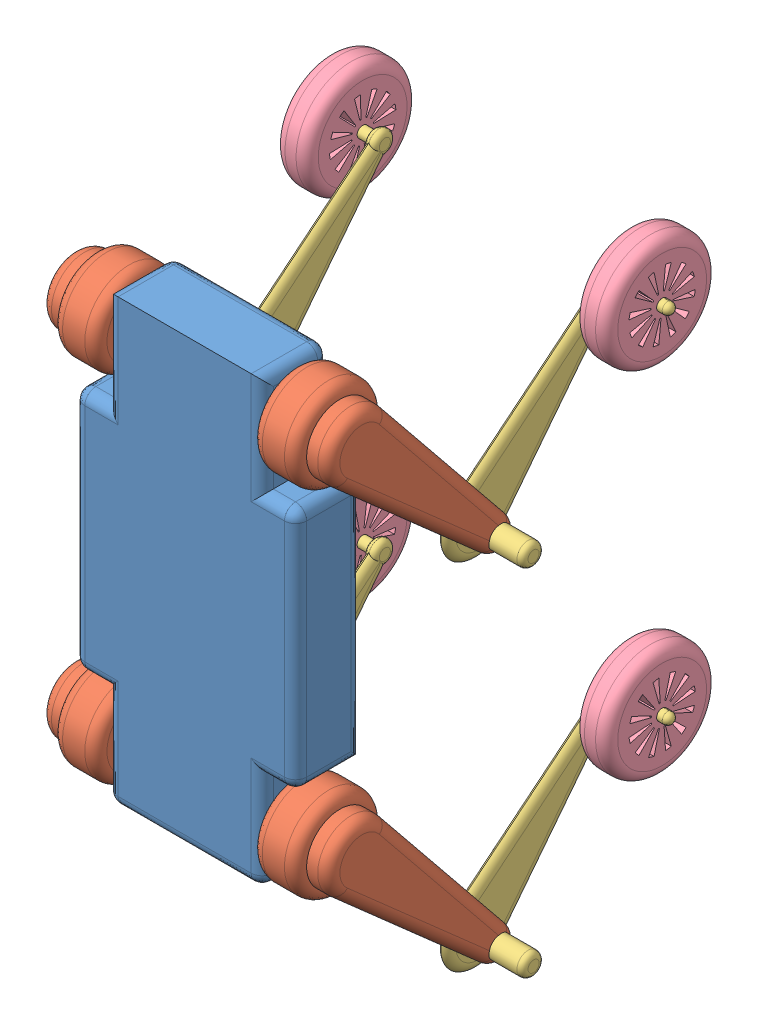
SolidWorks assembly Robot Assembly, configuration Default. Lengths in mm.
Overall size (320 555.26 377.09).
14 component instances, 5 part files, 32 mates.
Components (placement in the parent):
- Chassis-1: Chassis [Default] at (25.2853 23.51 279.6781) size (200 400 60)
- Leg Link-1: Leg Link [Default] at (235.2853 63.51 309.6781) x (1 0 0) z (0 0.721797 0.692105) size (100.59 80 235)
- Leg Link-2: Leg Link [Default] at (15.2853 383.51 309.6781) x (-1 0 0) z (0 0.721797 0.692105) size (100.59 80 235)
- Leg Link-3: Leg Link [Default] at (235.2853 383.51 309.6781) x (1 0 0) z (0 0.721797 0.692105) size (100.59 80 235)
- Leg Link-4: Leg Link [Default] at (15.2853 63.51 309.6781) x (-1 0 0) z (0 0.721797 0.692105) size (100.59 80 235)
- Part1^Robot Assembly-1: Part1^Robot Assembly [Default] at origin (virtual)
- Leg-1: Leg [Default] at (225.2853 -66.4135 185.0992) x (1 0 0) z (0 -0.714481 0.699655) size (60.46 57.32 218.66)
- Leg-2: Leg [Default] at (25.2853 253.5865 185.0992) x (-1 0 0) z (0 -0.714481 0.699655) size (60.46 57.32 218.66)
- Leg-3: Leg [Default] at (25.2853 -66.4135 185.0992) x (-1 0 0) z (0 -0.714481 0.699655) size (60.46 57.32 218.66)
- Leg-4: Leg [Default] at (225.2853 253.5865 185.0992) x (1 0 0) z (0 -0.714481 0.699655) size (60.46 57.32 218.66)
- Wheel-1: Wheel [Default] at (-24.7147 382.1931 59.1613) x (1 0 0) z (0 -0.969703 -0.244286) size (30 100 100)
- Wheel-2: Wheel [Default] at (245.2853 382.1931 59.1613) x (1 0 0) z (0 -0.911816 -0.410599) size (30 100 100)
- Wheel-3: Wheel [Default] at (-24.7147 62.1931 59.1613) x (1 0 0) z (0 -0.799104 0.601193) size (30 100 100)
- Wheel-4: Wheel [Default] at (245.2853 62.1931 59.1613) x (1 0 0) z (0 -0.274003 0.961729) size (30 100 100)
Mates (geometry in assembly coordinates):
- Concentric1: concentric: cylinder of Chassis-1 through (25.2853 63.51 309.6781) axis (1 0 0) radius 15; cylinder of Leg Link-1 through (155.2853 63.51 309.6781) axis (1 0 0) radius 15
- Coincident1: coincident: plane of Chassis-1 through (195.2853 113.51 339.6781) normal (1 0 0); plane of Leg Link-1 through (195.2853 63.51 309.6781) normal (-1 0 0)
- Concentric2: concentric: cylinder of Chassis-1 through (25.2853 63.51 309.6781) axis (1 0 0) radius 15; cylinder of Leg Link-4 through (95.2853 63.51 309.6781) axis (-1 0 0) radius 15
- Coincident2: coincident: plane of Chassis-1 through (55.2853 113.51 339.6781) normal (-1 0 0); plane of Leg Link-4 through (55.2853 63.51 309.6781) normal (1 0 0)
- Concentric3: concentric: cylinder of Chassis-1 through (25.2853 383.51 309.6781) axis (1 0 0) radius 15; cylinder of Leg Link-2 through (95.2853 383.51 309.6781) axis (-1 0 0) radius 15
- Coincident4: coincident: plane of Chassis-1 through (55.2853 333.51 339.6781) normal (-1 0 0); plane of Leg Link-2 through (55.2853 383.51 309.6781) normal (1 0 0)
- Concentric4: concentric: cylinder of Chassis-1 through (25.2853 383.51 309.6781) axis (1 0 0) radius 15; cylinder of Leg Link-3 through (155.2853 383.51 309.6781) axis (1 0 0) radius 15
- Coincident5: coincident: plane of Chassis-1 through (195.2853 333.51 339.6781) normal (1 0 0); plane of Leg Link-3 through (195.2853 383.51 309.6781) normal (-1 0 0)
- Concentric5: concentric: cylinder of Leg Link-1 through (155.2853 -66.4135 185.0992) axis (1 0 0) radius 10; cylinder of Leg-1 through (285.2853 -66.4135 185.0992) axis (-1 0 0) radius 10
- Coincident6: coincident: plane of Leg Link-1 through (235.2853 63.51 309.6781) normal (-1 0 0); plane of Leg-1 through (235.2853 -66.4135 185.0992) normal (1 0 0)
- Concentric6: concentric: cylinder of Leg Link-3 through (155.2853 253.5865 185.0992) axis (1 0 0) radius 10; cylinder of Leg-4 through (285.2853 253.5865 185.0992) axis (-1 0 0) radius 10
- Coincident7: coincident: plane of Leg Link-3 through (235.2853 383.51 309.6781) normal (-1 0 0); plane of Leg-4 through (235.2853 253.5865 185.0992) normal (1 0 0)
- Concentric7: concentric: cylinder of Leg Link-4 through (95.2853 -40.2556 162.5975) axis (-1 0 0) radius 10; cylinder of Leg-3 through (-34.7147 -40.2556 162.5975) axis (1 0 0) radius 10
- Coincident8: coincident: plane of Leg Link-4 through (15.2853 63.51 309.6781) normal (1 0 0); plane of Leg-3 through (15.2853 -40.2556 162.5975) normal (-1 0 0)
- Coincident9: coincident: plane of Leg Link-2 through (15.2853 383.51 309.6781) normal (1 0 0); plane of Leg-2 through (15.2853 253.5865 185.0992) normal (-1 0 0)
- Concentric8: concentric: cylinder of Leg Link-2 through (95.2853 253.5865 185.0992) axis (-1 0 0) radius 10; cylinder of Leg-2 through (-34.7147 253.5865 185.0992) axis (1 0 0) radius 10
- Concentric9: concentric: cylinder of Leg-2 through (-34.7147 382.1931 59.1613) axis (1 0 0) radius 5; cylinder of Wheel-1 through (-24.7147 382.1931 59.1613) axis (1 0 0) radius 5
- Concentric10: concentric: cylinder of Leg-4 through (285.2853 382.1931 59.1613) axis (-1 0 0) radius 5; cylinder of Wheel-2 through (245.2853 382.1931 59.1613) axis (1 0 0) radius 5
- Concentric11: concentric: cylinder of Leg-3 through (-34.7147 110.0182 63.5128) axis (1 0 0) radius 5; cylinder of Wheel-3 through (-24.7147 110.0182 63.5128) axis (1 0 0) radius 5
- Concentric12: concentric: cylinder of Leg-1 through (285.2853 62.1931 59.1613) axis (-1 0 0) radius 5; cylinder of Wheel-4 through (245.2853 62.1931 59.1613) axis (1 0 0) radius 5
- Distance2: distance = 10 mm: plane of Wheel-4 through (245.2853 62.1931 59.1613) normal (-1 0 0); plane of Leg-1 through (235.2853 -66.4135 185.0992) normal (1 0 0)
- Distance3: distance = 10 mm: plane of Wheel-2 through (245.2853 382.1931 59.1613) normal (-1 0 0); plane of Leg-4 through (235.2853 253.5865 185.0992) normal (1 0 0)
- Distance4: distance = 10 mm: plane of Wheel-3 through (5.2853 62.1931 59.1613) normal (1 0 0); plane of Leg-3 through (15.2853 -66.4135 185.0992) normal (-1 0 0)
- Distance5: distance = 10 mm: plane of Wheel-1 through (5.2853 382.1931 59.1613) normal (1 0 0); plane of Leg-2 through (15.2853 253.5865 185.0992) normal (-1 0 0)
- Angle2: planar angle = 2.460914 rad: line of Leg Link-1 through (255.2853 -56.5462 186.7234) axis (0 0.777146 0.62932); line of Chassis-1 through (215.2853 333.51 279.6781) axis (0 -1 0)
- Angle3: planar angle = 0.680678 rad: line of Leg Link-4 through (-4.7147 76.0964 294.1352) axis (0 -0.777146 -0.62932); line of Chassis-1 through (25.2853 323.51 289.6781) axis (0 -1 0)
- Angle4: planar angle = 0.680678 rad: line of Leg Link-3 through (255.2853 263.4538 186.7234) axis (0 0.777146 0.62932); line of Chassis-1 through (225.2853 123.51 289.6781) axis (0 1 0)
- Angle5: planar angle = 0.680678 rad: line of Leg Link-2 through (-4.7147 396.0964 294.1352) axis (0 -0.777146 -0.62932); line of Chassis-1 through (25.2853 323.51 289.6781) axis (0 -1 0)
- Angle6: planar angle = 1.343904 rad: line of Leg Link-1 through (255.2853 -56.5462 186.7234) axis (0 0.777146 0.62932); line of Leg-1 through (235.2853 -78.7267 169.339) axis (0 0.788011 -0.615661)
- Angle7: planar angle = 1.343904 rad: line of Leg-3 through (15.2853 58.2917 62.2885) axis (0 -0.788011 0.615661); line of Leg Link-4 through (-4.7147 76.0964 294.1352) axis (0 -0.777146 -0.62932)
- Angle8: planar angle = 1.343904 rad: line of Leg-2 through (15.2853 378.2917 62.2885) axis (0 -0.788011 0.615661); line of Leg Link-2 through (-4.7147 396.0964 294.1352) axis (0 -0.777146 -0.62932)
- Angle9: planar angle = 1.343904 rad: line of Leg-4 through (235.2853 241.2733 169.339) axis (0 0.788011 -0.615661); line of Leg Link-3 through (255.2853 263.4538 186.7234) axis (0 0.777146 0.62932)
